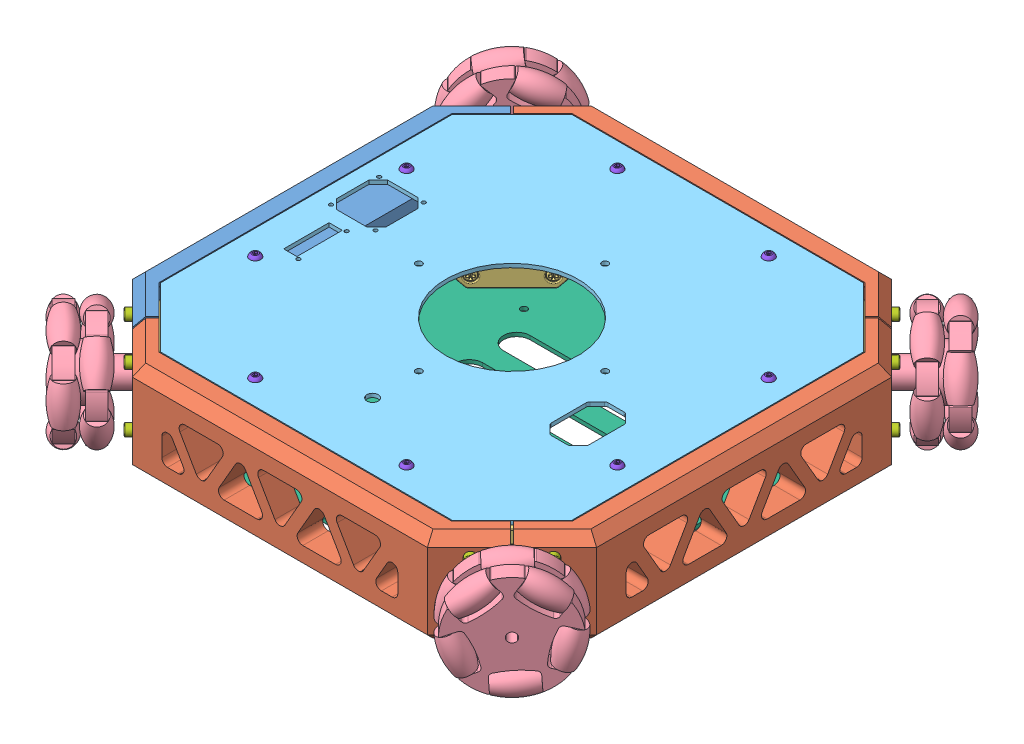
SolidWorks assembly 装配体1 - 副本, configuration 默认. Lengths in mm.
Overall size (303.95 82.91 303.97).
46 component instances, 8 part files, 98 mates.
Components (placement in the parent):
- 边框2-1: 边框2 [默认] at (-52.5924 -38.2864 100) size (40 50 200)
- 边框-6: 边框 [默认] at (-7.8853 -38.2864 -100.7071) x (0 0 1) z (-1 0 0) size (40 50 200)
- 边框-7: 边框 [默认] at (148.1147 -38.2864 144.7071) x (0 0 -1) z (1 0 0) size (40 50 200)
- 4248步进电机-1: 4248步进电机 [По умолчанию] at (10.7726 -13.2864 81.3421) x (0.707107 0 0.707107) z (0 -1 0) size (42.3 72 42.32)
- 4248步进电机-2: 4248步进电机 [По умолчанию] at (10.7726 -13.2864 -37.3421) x (-0.707107 0 0.707107) z (0 -1 0) size (42.3 72 42.32)
- 福来轮-1: 福来轮 [默认] at (-42.6132 -13.2864 134.7279) x (-0.643511 -0.414472 -0.643511) z (0.707107 0 -0.707107) size (58.57 59.14 32.85)
- 福来轮-2: 福来轮 [默认] at (-42.6132 -13.2864 -90.7279) x (0.643511 -0.414472 -0.643511) z (0.707107 0 0.707107) size (58.57 59.14 32.85)
- 边框-8: 边框 [默认] at (192.8218 -38.2864 -56) x (-1 0 0) z (0 0 -1) size (40 50 200)
- 4248步进电机-3: 4248步进电机 [По умолчанию] at (129.4568 -13.2864 -37.3421) x (-0.707107 0 -0.707107) z (0 -1 0) size (42.3 72 42.32)
- 4248步进电机-4: 4248步进电机 [По умолчанию] at (129.4568 -13.2864 81.3421) x (0.707107 0 -0.707107) z (0 -1 0) size (42.3 72 42.32)
- 福来轮-3: 福来轮 [默认] at (182.8426 -13.2864 -90.7279) x (0.643511 -0.414472 0.643511) z (-0.707107 0 0.707107) size (58.57 59.14 32.85)
- 福来轮-4: 福来轮 [默认] at (182.8426 -13.2864 134.7279) x (0.544603 0.637821 -0.544603) z (-0.707107 0 -0.707107) size (58.57 59.14 32.85)
- 顶板-2: 顶板 [默认] at (-38.5777 9.7136 89.3751) size (217.38 2 217.38)
- 底板-2: 底板 [默认] at (-38.5777 -38.2864 89.3751) size (217.38 2 217.38)
- hexagon socket head cap screws gb-15: hexagon socket head cap screws gb [GB_FASTENER_SCREWS_HSHCS M3X16-N] at (-43.3203 2.2136 113.5147) x (0.707107 0 -0.707107) z (0.707107 0 0.707107) size (19 5.5 5.5)
- hexagon socket head cap screws gb-16: hexagon socket head cap screws gb [GB_FASTENER_SCREWS_HSHCS M3X16-N] at (-21.4 2.2136 135.435) x (0.707107 0 -0.707107) z (0.707107 0 0.707107) size (19 5.5 5.5)
- hexagon socket head cap screws gb-17: hexagon socket head cap screws gb [GB_FASTENER_SCREWS_HSHCS M3X16-N] at (-43.3203 -28.7864 113.5147) x (0.707107 0 -0.707107) z (0.707107 0 0.707107) size (19 5.5 5.5)
- hexagon socket head cap screws gb-18: hexagon socket head cap screws gb [GB_FASTENER_SCREWS_HSHCS M3X16-N] at (-21.4 -28.7864 135.435) x (0.707107 0 -0.707107) z (0.707107 0 0.707107) size (19 5.5 5.5)
- hexagon socket head cap screws gb-19: hexagon socket head cap screws gb [GB_FASTENER_SCREWS_HSHCS M3X16-N] at (161.6294 2.2136 135.435) x (-0.707107 0 -0.707107) z (0.707107 0 -0.707107) size (19 5.5 5.5)
- hexagon socket head cap screws gb-20: hexagon socket head cap screws gb [GB_FASTENER_SCREWS_HSHCS M3X16-N] at (161.6294 -28.7864 135.435) x (-0.707107 0 -0.707107) z (0.707107 0 -0.707107) size (19 5.5 5.5)
- hexagon socket head cap screws gb-21: hexagon socket head cap screws gb [GB_FASTENER_SCREWS_HSHCS M3X16-N] at (183.5497 2.2136 113.5147) x (-0.707107 0 -0.707107) z (0.707107 0 -0.707107) size (19 5.5 5.5)
- hexagon socket head cap screws gb-22: hexagon socket head cap screws gb [GB_FASTENER_SCREWS_HSHCS M3X16-N] at (183.5497 -28.7864 113.5147) x (-0.707107 0 -0.707107) z (0.707107 0 -0.707107) size (19 5.5 5.5)
- hexagon socket head cap screws gb-23: hexagon socket head cap screws gb [GB_FASTENER_SCREWS_HSHCS M3X16-N] at (183.5497 2.2136 -69.5147) x (-0.707107 0 0.707107) z (-0.707107 0 -0.707107) size (19 5.5 5.5)
- hexagon socket head cap screws gb-24: hexagon socket head cap screws gb [GB_FASTENER_SCREWS_HSHCS M3X16-N] at (183.5497 -28.7864 -69.5147) x (-0.707107 0 0.707107) z (-0.707107 0 -0.707107) size (19 5.5 5.5)
- hexagon socket head cap screws gb-25: hexagon socket head cap screws gb [GB_FASTENER_SCREWS_HSHCS M3X16-N] at (161.6294 2.2136 -91.435) x (-0.707107 0 0.707107) z (-0.707107 0 -0.707107) size (19 5.5 5.5)
- hexagon socket head cap screws gb-26: hexagon socket head cap screws gb [GB_FASTENER_SCREWS_HSHCS M3X16-N] at (161.6294 -28.7864 -91.435) x (-0.707107 0 0.707107) z (-0.707107 0 -0.707107) size (19 5.5 5.5)
- hexagon socket head cap screws gb-27: hexagon socket head cap screws gb [GB_FASTENER_SCREWS_HSHCS M3X16-N] at (-21.4 2.2136 -91.435) x (0.707107 0 0.707107) z (-0.707107 0 0.707107) size (19 5.5 5.5)
- hexagon socket head cap screws gb-28: hexagon socket head cap screws gb [GB_FASTENER_SCREWS_HSHCS M3X16-N] at (-21.4 -28.7864 -91.435) x (0.707107 0 0.707107) z (-0.707107 0 0.707107) size (19 5.5 5.5)
- hexagon socket head cap screws gb-29: hexagon socket head cap screws gb [GB_FASTENER_SCREWS_HSHCS M3X16-N] at (-43.3203 2.2136 -69.5147) x (0.707107 0 0.707107) z (-0.707107 0 0.707107) size (19 5.5 5.5)
- hexagon socket head cap screws gb-30: hexagon socket head cap screws gb [GB_FASTENER_SCREWS_HSHCS M3X16-N] at (-43.3203 -28.7864 -69.5147) x (0.707107 0 0.707107) z (-0.707107 0 0.707107) size (19 5.5 5.5)
- hexagon socket button head screws gb-53: hexagon socket button head screws gb [GB_SOCKET_TYPE7 M3X12-N] at (-25.5924 13.3636 -18) x (0 -1 0) z (0 0 1) size (13.65 5.7 5.7)
- hexagon socket button head screws gb-54: hexagon socket button head screws gb [GB_SOCKET_TYPE7 M3X12-N] at (-25.5924 13.3636 62) x (0 -1 0) z (0 0 1) size (13.65 5.7 5.7)
- hexagon socket button head screws gb-55: hexagon socket button head screws gb [GB_SOCKET_TYPE7 M3X12-N] at (30.1147 13.3636 117.7071) x (0 -1 0) z (0 0 1) size (13.65 5.7 5.7)
- hexagon socket button head screws gb-56: hexagon socket button head screws gb [GB_SOCKET_TYPE7 M3X12-N] at (110.1147 13.3636 117.7071) x (0 -1 0) z (0 0 1) size (13.65 5.7 5.7)
- hexagon socket button head screws gb-57: hexagon socket button head screws gb [GB_SOCKET_TYPE7 M3X12-N] at (165.8218 13.3636 62) x (0 -1 0) z (0 0 1) size (13.65 5.7 5.7)
- hexagon socket button head screws gb-58: hexagon socket button head screws gb [GB_SOCKET_TYPE7 M3X12-N] at (165.8218 13.3636 -18) x (0 -1 0) z (0 0 1) size (13.65 5.7 5.7)
- hexagon socket button head screws gb-59: hexagon socket button head screws gb [GB_SOCKET_TYPE7 M3X12-N] at (110.1147 13.3636 -73.7071) x (0 -1 0) z (0 0 1) size (13.65 5.7 5.7)
- hexagon socket button head screws gb-60: hexagon socket button head screws gb [GB_SOCKET_TYPE7 M3X12-N] at (30.1147 13.3636 -73.7071) x (0 -1 0) z (0 0 1) size (13.65 5.7 5.7)
- hexagon socket button head screws gb-61: hexagon socket button head screws gb [GB_SOCKET_TYPE7 M3X12-N] at (11.7609 -39.9364 -79.1924) x (0 1 0) z (0 0 1) size (13.65 5.7 5.7)
- hexagon socket button head screws gb-62: hexagon socket button head screws gb [GB_SOCKET_TYPE7 M3X12-N] at (-31.0777 -39.9364 -36.3538) x (0 1 0) z (0 0 1) size (13.65 5.7 5.7)
- hexagon socket button head screws gb-63: hexagon socket button head screws gb [GB_SOCKET_TYPE7 M3X12-N] at (-31.0777 -39.9364 80.3538) x (0 1 0) z (0 0 1) size (13.65 5.7 5.7)
- hexagon socket button head screws gb-64: hexagon socket button head screws gb [GB_SOCKET_TYPE7 M3X12-N] at (11.7609 -39.9364 123.1924) x (0 1 0) z (0 0 1) size (13.65 5.7 5.7)
- hexagon socket button head screws gb-65: hexagon socket button head screws gb [GB_SOCKET_TYPE7 M3X12-N] at (128.4685 -39.9364 123.1924) x (0 1 0) z (0 0 1) size (13.65 5.7 5.7)
- hexagon socket button head screws gb-66: hexagon socket button head screws gb [GB_SOCKET_TYPE7 M3X12-N] at (171.3071 -39.9364 80.3538) x (0 1 0) z (0 0 1) size (13.65 5.7 5.7)
- hexagon socket button head screws gb-67: hexagon socket button head screws gb [GB_SOCKET_TYPE7 M3X12-N] at (171.3071 -39.9364 -36.3538) x (0 1 0) z (0 0 1) size (13.65 5.7 5.7)
- hexagon socket button head screws gb-68: hexagon socket button head screws gb [GB_SOCKET_TYPE7 M3X12-N] at (128.4685 -39.9364 -79.1924) x (0 1 0) z (0 0 1) size (13.65 5.7 5.7)
Mates (geometry in assembly coordinates):
- 重合2: coincident anti-aligned: plane of 边框-1 through (-39.0777 11.7136 99.3726) normal (0.707107 0 -0.707107); plane of 4248步进电机-1 through (-23.1678 -13.2864 115.2825) normal (-0.707107 0 0.707107)
- 同心1: concentric anti-aligned: cylinder of 边框-1 through (-76.5544 2.2136 146.7487) axis (0.707107 0 -0.707107) radius 1.7; cylinder of 4248步进电机-1 through (-34.1287 2.2136 104.323) axis (-0.707107 0 0.707107) radius 1.25
- 同心2: concentric anti-aligned: cylinder of 边框-1 through (-76.5544 -28.7864 146.7487) axis (0.707107 0 -0.707107) radius 1.7; cylinder of 4248步进电机-1 through (-34.1287 -28.7864 104.323) axis (-0.707107 0 0.707107) radius 1.25
- 重合4: coincident anti-aligned: plane of 边框-1 through (-23.5213 11.7136 -70.9289) normal (0.707107 0 0.707107); plane of 4248步进电机-2 through (-23.1678 -13.2864 -71.2825) normal (-0.707107 0 -0.707107)
- 同心5: concentric anti-aligned: cylinder of 边框-1 through (-76.5544 2.2136 -102.7487) axis (0.707107 0 0.707107) radius 1.7; cylinder of 4248步进电机-2 through (-34.1287 2.2136 -60.323) axis (-0.707107 0 -0.707107) radius 1.25
- 同心6: concentric anti-aligned: cylinder of 边框-1 through (-76.5544 -28.7864 -102.7487) axis (0.707107 0 0.707107) radius 1.7; cylinder of 4248步进电机-2 through (-34.1287 -28.7864 -60.323) axis (-0.707107 0 -0.707107) radius 1.25
- 重合5: coincident anti-aligned: plane of 边框-6 through (-7.2579 11.7136 -87.1924) normal (0.707107 0 0.707107); plane of 4248步进电机-2 through (-23.1678 -13.2864 -71.2825) normal (-0.707107 0 -0.707107)
- 同心7: concentric anti-aligned: cylinder of 边框-6 through (-54.634 -28.7864 -124.669) axis (0.707107 0 0.707107) radius 1.7; cylinder of 4248步进电机-2 through (-12.2083 -28.7864 -82.2433) axis (-0.707107 0 -0.707107) radius 1.25
- 同心8: concentric anti-aligned: cylinder of 4248步进电机-1 through (-40.1391 -13.2864 132.2538) axis (0.707107 0 -0.707107) radius 2.5; cylinder of 福来轮-1 through (-30.2389 -13.2864 122.3536) axis (-0.707107 0 0.707107) radius 7
- 同心9: concentric anti-aligned: cylinder of 4248步进电机-2 through (-40.1391 -13.2864 -88.2538) axis (0.707107 0 0.707107) radius 2.5; cylinder of 福来轮-2 through (-30.2389 -13.2864 -78.3536) axis (-0.707107 0 -0.707107) radius 7
- 重合7: coincident anti-aligned: plane of 边框-6 through (-29.8853 11.7136 -78.7071) normal (-0.707107 0 -0.707107); plane of 福来轮-2 through (-30.2389 -13.2864 -78.3536) normal (0.707107 0 0.707107)
- 重合8: coincident anti-aligned: plane of 边框-7 through (-22.8142 11.7136 115.636) normal (0.707107 0 -0.707107); plane of 4248步进电机-1 through (-23.1678 -13.2864 115.2825) normal (-0.707107 0 0.707107)
- 同心10: concentric anti-aligned: cylinder of 边框-7 through (-54.634 2.2136 168.669) axis (0.707107 0 -0.707107) radius 1.7; cylinder of 4248步进电机-1 through (-12.2083 2.2136 126.2433) axis (-0.707107 0 0.707107) radius 1.25
- 同心11: concentric anti-aligned: cylinder of 边框-7 through (-54.634 -28.7864 168.669) axis (0.707107 0 -0.707107) radius 1.7; cylinder of 4248步进电机-1 through (-12.2083 -28.7864 126.2433) axis (-0.707107 0 0.707107) radius 1.25
- 重合9: coincident anti-aligned: plane of 边框-6 through (163.0436 11.7136 -71.636) normal (-0.707107 0 0.707107); plane of 4248步进电机-3 through (163.3972 -13.2864 -71.2825) normal (0.707107 0 -0.707107)
- 同心12: concentric anti-aligned: cylinder of 边框-6 through (194.8634 2.2136 -124.669) axis (-0.707107 0 0.707107) radius 1.7; cylinder of 4248步进电机-3 through (152.4377 2.2136 -82.2433) axis (0.707107 0 -0.707107) radius 1.25
- 同心13: concentric anti-aligned: cylinder of 边框-6 through (194.8634 -28.7864 -124.669) axis (-0.707107 0 0.707107) radius 1.7; cylinder of 4248步进电机-3 through (152.4377 -28.7864 -82.2433) axis (0.707107 0 -0.707107) radius 1.25
- 重合10: coincident anti-aligned: plane of 边框-8 through (179.3071 11.7136 -55.3726) normal (-0.707107 0 0.707107); plane of 4248步进电机-3 through (163.3972 -13.2864 -71.2825) normal (0.707107 0 -0.707107)
- 同心14: concentric anti-aligned: cylinder of 边框-8 through (216.7837 2.2136 -102.7487) axis (-0.707107 0 0.707107) radius 1.7; cylinder of 4248步进电机-3 through (174.358 2.2136 -60.323) axis (0.707107 0 -0.707107) radius 1.25
- 同心15: concentric anti-aligned: cylinder of 边框-8 through (216.7837 -28.7864 -102.7487) axis (-0.707107 0 0.707107) radius 1.7; cylinder of 4248步进电机-3 through (174.358 -28.7864 -60.323) axis (0.707107 0 -0.707107) radius 1.25
- 重合11: coincident anti-aligned: plane of 边框-8 through (163.7507 11.7136 114.9289) normal (-0.707107 0 -0.707107); plane of 4248步进电机-4 through (163.3972 -13.2864 115.2825) normal (0.707107 0 0.707107)
- 同心16: concentric anti-aligned: cylinder of 边框-7 through (194.8634 -28.7864 168.669) axis (-0.707107 0 -0.707107) radius 1.7; cylinder of 4248步进电机-4 through (152.4377 -28.7864 126.2433) axis (0.707107 0 0.707107) radius 1.25
- 同心18: concentric anti-aligned: cylinder of 边框-7 through (194.8634 2.2136 168.669) axis (-0.707107 0 -0.707107) radius 1.7; cylinder of 4248步进电机-4 through (152.4377 2.2136 126.2433) axis (0.707107 0 0.707107) radius 1.25
- 同心19: concentric anti-aligned: cylinder of 边框-6 through (-54.634 2.2136 -124.669) axis (0.707107 0 0.707107) radius 1.7; cylinder of 4248步进电机-2 through (-12.2083 2.2136 -82.2433) axis (-0.707107 0 -0.707107) radius 1.25
- 同心20: concentric anti-aligned: cylinder of 4248步进电机-3 through (180.3684 -13.2864 -88.2538) axis (-0.707107 0 0.707107) radius 2.5; cylinder of 福来轮-3 through (170.4682 -13.2864 -78.3536) axis (0.707107 0 -0.707107) radius 7
- 重合12: coincident anti-aligned: plane of 边框-8 through (170.8218 11.7136 -78) normal (0.707107 0 -0.707107); plane of 福来轮-3 through (170.4682 -13.2864 -78.3536) normal (-0.707107 0 0.707107)
- 同心21: concentric anti-aligned: cylinder of 4248步进电机-4 through (180.3684 -13.2864 132.2538) axis (-0.707107 0 -0.707107) radius 2.5; cylinder of 福来轮-4 through (170.4682 -13.2864 122.3536) axis (0.707107 0 0.707107) radius 7
- 重合13: coincident anti-aligned: plane of 边框-7 through (170.1147 11.7136 122.7071) normal (0.707107 0 0.707107); plane of 福来轮-4 through (170.4682 -13.2864 122.3536) normal (-0.707107 0 -0.707107)
- 重合14: coincident anti-aligned: plane of 边框-7 through (148.1147 9.7136 144.7071) normal (0 1 0); plane of 顶板-2 through (-38.5777 9.7136 89.3751) normal (0 -1 0)
- 距离2: distance = 0.5 mm anti-aligned: plane of 顶板-2 through (-7.0508 11.7136 -86.6924) normal (0 0 -1); plane of 边框-6 through (147.4873 9.7136 -87.1924) normal (0 0 1)
- 距离3: distance = 0.5 mm anti-aligned: plane of 边框-1 through (-39.0777 9.7136 -55.3726) normal (1 0 0); plane of 顶板-2 through (-38.5777 11.7136 99.1655) normal (-1 0 0)
- 重合15: coincident anti-aligned: plane of 边框-8 through (192.8218 -36.2864 -56) normal (0 -1 0); plane of 底板-2 through (-38.5777 -36.2864 89.3751) normal (0 1 0)
- 距离4: distance = 0.5 mm anti-aligned: plane of 底板-2 through (147.2802 -36.2864 130.6924) normal (0 0 1); plane of 边框-7 through (147.4873 -36.2864 131.1924) normal (0 0 -1)
- 距离5: distance = 0.5 mm anti-aligned: plane of 边框-1 through (-39.0777 -36.2864 99.3726) normal (1 0 0); plane of 底板-2 through (-38.5777 -36.2864 99.1655) normal (-1 0 0)
- 同心198: concentric anti-aligned: cylinder of 边框-1 through (-76.5544 2.2136 146.7487) axis (0.707107 0 -0.707107) radius 1.7; cylinder of hexagon socket head cap screws gb-15 through (-29.8853 2.2136 100.0797) axis (-0.707107 0 0.707107) radius 1.5
- 重合174: coincident anti-aligned: plane of 边框-1 through (-30.5924 11.7136 122) normal (-0.707107 0 0.707107); plane of hexagon socket head cap screws gb-15 through (-41.199 2.2136 111.3934) normal (0.707107 0 -0.707107)
- 同心199: concentric anti-aligned: cylinder of 边框-7 through (-54.634 2.2136 168.669) axis (0.707107 0 -0.707107) radius 1.7; cylinder of hexagon socket head cap screws gb-16 through (-7.965 2.2136 122) axis (-0.707107 0 0.707107) radius 1.5
- 重合175: coincident anti-aligned: plane of 边框-7 through (-7.8853 11.7136 144.7071) normal (-0.707107 0 0.707107); plane of hexagon socket head cap screws gb-16 through (-19.2787 2.2136 133.3137) normal (0.707107 0 -0.707107)
- 同心200: concentric anti-aligned: cylinder of 边框-1 through (-76.5544 -28.7864 146.7487) axis (0.707107 0 -0.707107) radius 1.7; cylinder of hexagon socket head cap screws gb-17 through (-29.8853 -28.7864 100.0797) axis (-0.707107 0 0.707107) radius 1.5
- 重合176: coincident anti-aligned: plane of 边框-1 through (-30.5924 11.7136 122) normal (-0.707107 0 0.707107); plane of hexagon socket head cap screws gb-17 through (-41.199 -28.7864 111.3934) normal (0.707107 0 -0.707107)
- 同心201: concentric anti-aligned: cylinder of 边框-7 through (-54.634 -28.7864 168.669) axis (0.707107 0 -0.707107) radius 1.7; cylinder of hexagon socket head cap screws gb-18 through (-7.965 -28.7864 122) axis (-0.707107 0 0.707107) radius 1.5
- 重合177: coincident anti-aligned: plane of 边框-7 through (-7.8853 11.7136 144.7071) normal (-0.707107 0 0.707107); plane of hexagon socket head cap screws gb-18 through (-19.2787 -28.7864 133.3137) normal (0.707107 0 -0.707107)
- 同心202: concentric anti-aligned: cylinder of 边框-7 through (194.8634 2.2136 168.669) axis (-0.707107 0 -0.707107) radius 1.7; cylinder of hexagon socket head cap screws gb-19 through (148.1944 2.2136 122) axis (0.707107 0 0.707107) radius 1.5
- 重合178: coincident anti-aligned: plane of 边框-7 through (170.1147 11.7136 122.7071) normal (0.707107 0 0.707107); plane of hexagon socket head cap screws gb-19 through (159.5081 2.2136 133.3137) normal (-0.707107 0 -0.707107)
- 同心203: concentric anti-aligned: cylinder of 边框-7 through (194.8634 -28.7864 168.669) axis (-0.707107 0 -0.707107) radius 1.7; cylinder of hexagon socket head cap screws gb-20 through (148.1944 -28.7864 122) axis (0.707107 0 0.707107) radius 1.5
- 重合179: coincident anti-aligned: plane of 边框-7 through (170.1147 11.7136 122.7071) normal (0.707107 0 0.707107); plane of hexagon socket head cap screws gb-20 through (159.5081 -28.7864 133.3137) normal (-0.707107 0 -0.707107)
- 同心204: concentric anti-aligned: cylinder of 边框-8 through (216.7837 2.2136 146.7487) axis (-0.707107 0 -0.707107) radius 1.7; cylinder of hexagon socket head cap screws gb-21 through (170.1147 2.2136 100.0797) axis (0.707107 0 0.707107) radius 1.5
- 重合180: coincident anti-aligned: plane of 边框-8 through (192.8218 11.7136 100) normal (0.707107 0 0.707107); plane of hexagon socket head cap screws gb-21 through (181.4284 2.2136 111.3934) normal (-0.707107 0 -0.707107)
- 同心205: concentric anti-aligned: cylinder of 边框-8 through (216.7837 -28.7864 146.7487) axis (-0.707107 0 -0.707107) radius 1.7; cylinder of hexagon socket head cap screws gb-22 through (170.1147 -28.7864 100.0797) axis (0.707107 0 0.707107) radius 1.5
- 重合181: coincident anti-aligned: plane of 边框-8 through (192.8218 11.7136 100) normal (0.707107 0 0.707107); plane of hexagon socket head cap screws gb-22 through (181.4284 -28.7864 111.3934) normal (-0.707107 0 -0.707107)
- 同心206: concentric anti-aligned: cylinder of 边框-8 through (216.7837 2.2136 -102.7487) axis (-0.707107 0 0.707107) radius 1.7; cylinder of hexagon socket head cap screws gb-23 through (170.1147 2.2136 -56.0797) axis (0.707107 0 -0.707107) radius 1.5
- 重合182: coincident anti-aligned: plane of 边框-8 through (170.8218 11.7136 -78) normal (0.707107 0 -0.707107); plane of hexagon socket head cap screws gb-23 through (181.4284 2.2136 -67.3934) normal (-0.707107 0 0.707107)
- 同心207: concentric anti-aligned: cylinder of 边框-8 through (216.7837 -28.7864 -102.7487) axis (-0.707107 0 0.707107) radius 1.7; cylinder of hexagon socket head cap screws gb-24 through (170.1147 -28.7864 -56.0797) axis (0.707107 0 -0.707107) radius 1.5
- 重合183: coincident anti-aligned: plane of 边框-8 through (170.8218 11.7136 -78) normal (0.707107 0 -0.707107); plane of hexagon socket head cap screws gb-24 through (181.4284 -28.7864 -67.3934) normal (-0.707107 0 0.707107)
- 同心208: concentric anti-aligned: cylinder of 边框-6 through (194.8634 2.2136 -124.669) axis (-0.707107 0 0.707107) radius 1.7; cylinder of hexagon socket head cap screws gb-25 through (148.1944 2.2136 -78) axis (0.707107 0 -0.707107) radius 1.5
- 重合184: coincident anti-aligned: plane of 边框-6 through (148.1147 11.7136 -100.7071) normal (0.707107 0 -0.707107); plane of hexagon socket head cap screws gb-25 through (159.5081 2.2136 -89.3137) normal (-0.707107 0 0.707107)
- 同心209: concentric anti-aligned: cylinder of 边框-6 through (194.8634 -28.7864 -124.669) axis (-0.707107 0 0.707107) radius 1.7; cylinder of hexagon socket head cap screws gb-26 through (148.1944 -28.7864 -78) axis (0.707107 0 -0.707107) radius 1.5
- 重合185: coincident anti-aligned: plane of 边框-6 through (148.1147 11.7136 -100.7071) normal (0.707107 0 -0.707107); plane of hexagon socket head cap screws gb-26 through (159.5081 -28.7864 -89.3137) normal (-0.707107 0 0.707107)
- 同心210: concentric anti-aligned: cylinder of 边框-6 through (-54.634 2.2136 -124.669) axis (0.707107 0 0.707107) radius 1.7; cylinder of hexagon socket head cap screws gb-27 through (-7.965 2.2136 -78) axis (-0.707107 0 -0.707107) radius 1.5
- 重合186: coincident anti-aligned: plane of 边框-6 through (-29.8853 11.7136 -78.7071) normal (-0.707107 0 -0.707107); plane of hexagon socket head cap screws gb-27 through (-19.2787 2.2136 -89.3137) normal (0.707107 0 0.707107)
- 同心211: concentric anti-aligned: cylinder of 边框-6 through (-54.634 -28.7864 -124.669) axis (0.707107 0 0.707107) radius 1.7; cylinder of hexagon socket head cap screws gb-28 through (-7.965 -28.7864 -78) axis (-0.707107 0 -0.707107) radius 1.5
- 重合187: coincident anti-aligned: plane of 边框-6 through (-29.8853 11.7136 -78.7071) normal (-0.707107 0 -0.707107); plane of hexagon socket head cap screws gb-28 through (-19.2787 -28.7864 -89.3137) normal (0.707107 0 0.707107)
- 同心212: concentric anti-aligned: cylinder of 边框-1 through (-76.5544 2.2136 -102.7487) axis (0.707107 0 0.707107) radius 1.7; cylinder of hexagon socket head cap screws gb-29 through (-29.8853 2.2136 -56.0797) axis (-0.707107 0 -0.707107) radius 1.5
- 重合188: coincident anti-aligned: plane of 边框-1 through (-52.5924 11.7136 -56) normal (-0.707107 0 -0.707107); plane of hexagon socket head cap screws gb-29 through (-41.199 2.2136 -67.3934) normal (0.707107 0 0.707107)
- 同心213: concentric anti-aligned: cylinder of 边框-1 through (-76.5544 -28.7864 -102.7487) axis (0.707107 0 0.707107) radius 1.7; cylinder of hexagon socket head cap screws gb-30 through (-29.8853 -28.7864 -56.0797) axis (-0.707107 0 -0.707107) radius 1.5
- 重合189: coincident anti-aligned: plane of 边框-1 through (-52.5924 11.7136 -56) normal (-0.707107 0 -0.707107); plane of hexagon socket head cap screws gb-30 through (-41.199 -28.7864 -67.3934) normal (0.707107 0 0.707107)
- 同心214: concentric anti-aligned: cylinder of 顶板-2 through (-25.5924 11.7136 -18) axis (0 -1 0) radius 2; cylinder of hexagon socket button head screws gb-53 through (-25.5924 -0.2864 -18) axis (0 1 0) radius 1.5
- 重合190: coincident anti-aligned: plane of 顶板-2 through (-38.5777 11.7136 89.3751) normal (0 1 0); plane of hexagon socket button head screws gb-53 through (-25.5924 11.7136 -18) normal (0 -1 0)
- 同心215: concentric anti-aligned: cylinder of 顶板-2 through (-25.5924 11.7136 62) axis (0 -1 0) radius 2; cylinder of hexagon socket button head screws gb-54 through (-25.5924 -0.2864 62) axis (0 1 0) radius 1.5
- 重合191: coincident anti-aligned: plane of 顶板-2 through (-38.5777 11.7136 89.3751) normal (0 1 0); plane of hexagon socket button head screws gb-54 through (-25.5924 11.7136 62) normal (0 -1 0)
- 同心216: concentric anti-aligned: cylinder of 顶板-2 through (30.1147 11.7136 117.7071) axis (0 -1 0) radius 2; cylinder of hexagon socket button head screws gb-55 through (30.1147 -0.2864 117.7071) axis (0 1 0) radius 1.5
- 重合192: coincident anti-aligned: plane of 顶板-2 through (-38.5777 11.7136 89.3751) normal (0 1 0); plane of hexagon socket button head screws gb-55 through (30.1147 11.7136 117.7071) normal (0 -1 0)
- 同心217: concentric anti-aligned: cylinder of 顶板-2 through (110.1147 11.7136 117.7071) axis (0 -1 0) radius 2; cylinder of hexagon socket button head screws gb-56 through (110.1147 -0.2864 117.7071) axis (0 1 0) radius 1.5
- 重合193: coincident anti-aligned: plane of 顶板-2 through (-38.5777 11.7136 89.3751) normal (0 1 0); plane of hexagon socket button head screws gb-56 through (110.1147 11.7136 117.7071) normal (0 -1 0)
- 同心218: concentric anti-aligned: cylinder of 顶板-2 through (165.8218 11.7136 62) axis (0 -1 0) radius 2; cylinder of hexagon socket button head screws gb-57 through (165.8218 -0.2864 62) axis (0 1 0) radius 1.5
- 重合194: coincident anti-aligned: plane of 顶板-2 through (-38.5777 11.7136 89.3751) normal (0 1 0); plane of hexagon socket button head screws gb-57 through (165.8218 11.7136 62) normal (0 -1 0)
- 同心219: concentric anti-aligned: cylinder of 顶板-2 through (165.8218 11.7136 -18) axis (0 -1 0) radius 2; cylinder of hexagon socket button head screws gb-58 through (165.8218 -0.2864 -18) axis (0 1 0) radius 1.5
- 重合195: coincident anti-aligned: plane of 顶板-2 through (-38.5777 11.7136 89.3751) normal (0 1 0); plane of hexagon socket button head screws gb-58 through (165.8218 11.7136 -18) normal (0 -1 0)
- 同心220: concentric anti-aligned: cylinder of 顶板-2 through (110.1147 11.7136 -73.7071) axis (0 -1 0) radius 2; cylinder of hexagon socket button head screws gb-59 through (110.1147 -0.2864 -73.7071) axis (0 1 0) radius 1.5
- 重合196: coincident anti-aligned: plane of 顶板-2 through (-38.5777 11.7136 89.3751) normal (0 1 0); plane of hexagon socket button head screws gb-59 through (110.1147 11.7136 -73.7071) normal (0 -1 0)
- 同心221: concentric anti-aligned: cylinder of 顶板-2 through (30.1147 11.7136 -73.7071) axis (0 -1 0) radius 2; cylinder of hexagon socket button head screws gb-60 through (30.1147 -0.2864 -73.7071) axis (0 1 0) radius 1.5
- 重合197: coincident anti-aligned: plane of 顶板-2 through (-38.5777 11.7136 89.3751) normal (0 1 0); plane of hexagon socket button head screws gb-60 through (30.1147 11.7136 -73.7071) normal (0 -1 0)
- 同心222: concentric aligned: cylinder of 底板-2 through (11.7609 -36.2864 -79.1924) axis (0 -1 0) radius 1.7; cylinder of hexagon socket button head screws gb-61 through (11.7609 -26.2864 -79.1924) axis (0 -1 0) radius 1.5
- 重合198: coincident anti-aligned: plane of 底板-2 through (-38.5777 -38.2864 89.3751) normal (0 -1 0); plane of hexagon socket button head screws gb-61 through (11.7609 -38.2864 -79.1924) normal (0 1 0)
- 同心223: concentric aligned: cylinder of 底板-2 through (-31.0777 -36.2864 -36.3538) axis (0 -1 0) radius 1.7; cylinder of hexagon socket button head screws gb-62 through (-31.0777 -26.2864 -36.3538) axis (0 -1 0) radius 1.5
- 重合199: coincident anti-aligned: plane of 底板-2 through (-38.5777 -38.2864 89.3751) normal (0 -1 0); plane of hexagon socket button head screws gb-62 through (-31.0777 -38.2864 -36.3538) normal (0 1 0)
- 同心224: concentric aligned: cylinder of 底板-2 through (-31.0777 -36.2864 80.3538) axis (0 -1 0) radius 1.7; cylinder of hexagon socket button head screws gb-63 through (-31.0777 -26.2864 80.3538) axis (0 -1 0) radius 1.5
- 重合200: coincident anti-aligned: plane of 底板-2 through (-38.5777 -38.2864 89.3751) normal (0 -1 0); plane of hexagon socket button head screws gb-63 through (-31.0777 -38.2864 80.3538) normal (0 1 0)
- 同心225: concentric aligned: cylinder of 底板-2 through (11.7609 -36.2864 123.1924) axis (0 -1 0) radius 1.7; cylinder of hexagon socket button head screws gb-64 through (11.7609 -26.2864 123.1924) axis (0 -1 0) radius 1.5
- 重合201: coincident anti-aligned: plane of 底板-2 through (-38.5777 -38.2864 89.3751) normal (0 -1 0); plane of hexagon socket button head screws gb-64 through (11.7609 -38.2864 123.1924) normal (0 1 0)
- 同心226: concentric aligned: cylinder of 底板-2 through (128.4685 -36.2864 123.1924) axis (0 -1 0) radius 1.7; cylinder of hexagon socket button head screws gb-65 through (128.4685 -26.2864 123.1924) axis (0 -1 0) radius 1.5
- 重合202: coincident anti-aligned: plane of 底板-2 through (-38.5777 -38.2864 89.3751) normal (0 -1 0); plane of hexagon socket button head screws gb-65 through (128.4685 -38.2864 123.1924) normal (0 1 0)
- 同心227: concentric aligned: cylinder of 底板-2 through (171.3071 -36.2864 80.3538) axis (0 -1 0) radius 1.7; cylinder of hexagon socket button head screws gb-66 through (171.3071 -26.2864 80.3538) axis (0 -1 0) radius 1.5
- 重合203: coincident anti-aligned: plane of 底板-2 through (-38.5777 -38.2864 89.3751) normal (0 -1 0); plane of hexagon socket button head screws gb-66 through (171.3071 -38.2864 80.3538) normal (0 1 0)
- 同心228: concentric aligned: cylinder of 底板-2 through (171.3071 -36.2864 -36.3538) axis (0 -1 0) radius 1.7; cylinder of hexagon socket button head screws gb-67 through (171.3071 -26.2864 -36.3538) axis (0 -1 0) radius 1.5
- 重合204: coincident anti-aligned: plane of 底板-2 through (-38.5777 -38.2864 89.3751) normal (0 -1 0); plane of hexagon socket button head screws gb-67 through (171.3071 -38.2864 -36.3538) normal (0 1 0)
- 同心229: concentric aligned: cylinder of 底板-2 through (128.4685 -36.2864 -79.1924) axis (0 -1 0) radius 1.7; cylinder of hexagon socket button head screws gb-68 through (128.4685 -26.2864 -79.1924) axis (0 -1 0) radius 1.5
- 重合205: coincident anti-aligned: plane of 底板-2 through (-38.5777 -38.2864 89.3751) normal (0 -1 0); plane of hexagon socket button head screws gb-68 through (128.4685 -38.2864 -79.1924) normal (0 1 0)
